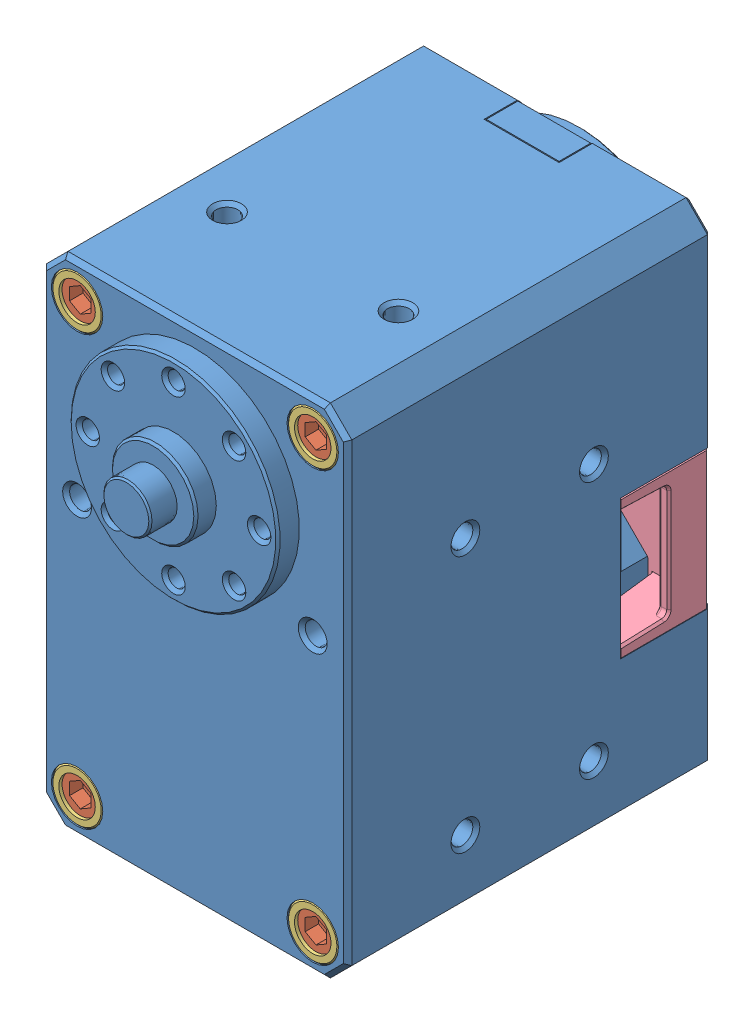
SolidWorks assembly XM430, configuration Default. Lengths in mm.
Overall size (28.5 46.5 42.4).
18 component instances, 4 part files, 0 mates.
Components (placement in the parent):
- DUMMY_DC12-1: DUMMY_DC12 [Default] at origin size (28.5 46.5 42.4)
- WBH_M2_5X12-1: WBH_M2_5X12 [Default] at (-11 8 14.2) size (4.5 4.5 14.5)
- WBH_M2_5X12-2: WBH_M2_5X12 [Default] at (11 8 14.2) size (4.5 4.5 14.5)
- WBH_M2_5X12-3: WBH_M2_5X12 [Default] at (-11 -32 14.2) size (4.5 4.5 14.5)
- WBH_M2_5X12-4: WBH_M2_5X12 [Default] at (11 -32 14.2) size (4.5 4.5 14.5)
- WBH_M2_5X12-5: WBH_M2_5X12 [Default] at (11 -32 -14.2) x (-1 0 0) z (0 0 -1) size (4.5 4.5 14.5)
- WBH_M2_5X12-6: WBH_M2_5X12 [Default] at (-11 -32 -14.2) x (-1 0 0) z (0 0 -1) size (4.5 4.5 14.5)
- WBH_M2_5X12-7: WBH_M2_5X12 [Default] at (11 8 -14.2) x (-1 0 0) z (0 0 -1) size (4.5 4.5 14.5)
- WBH_M2_5X12-8: WBH_M2_5X12 [Default] at (-11 8 -14.2) x (-1 0 0) z (0 0 -1) size (4.5 4.5 14.5)
- DC12_A01_SPACER_RING_1-1: DC12_A01_SPACER_RING_1 [Default] at (11 8 -14.2) x (1 0 0) z (0 1 0) size (4.8 2.8 4.8)
- DC12_A01_SPACER_RING_1-2: DC12_A01_SPACER_RING_1 [Default] at (-11 8 -14.2) x (1 0 0) z (0 1 0) size (4.8 2.8 4.8)
- DC12_A01_SPACER_RING_1-3: DC12_A01_SPACER_RING_1 [Default] at (11 -32 -14.2) x (1 0 0) z (0 1 0) size (4.8 2.8 4.8)
- DC12_A01_SPACER_RING_1-4: DC12_A01_SPACER_RING_1 [Default] at (-11 -32 -14.2) x (1 0 0) z (0 1 0) size (4.8 2.8 4.8)
- DC12_A01_SPACER_RING_1-5: DC12_A01_SPACER_RING_1 [Default] at (-11 -32 14.2) x (-1 0 0) z (0 1 0) size (4.8 2.8 4.8)
- DC12_A01_SPACER_RING_1-6: DC12_A01_SPACER_RING_1 [Default] at (11 -32 14.2) x (-1 0 0) z (0 1 0) size (4.8 2.8 4.8)
- DC12_A01_SPACER_RING_1-7: DC12_A01_SPACER_RING_1 [Default] at (-11 8 14.2) x (-1 0 0) z (0 1 0) size (4.8 2.8 4.8)
- DC12_A01_SPACER_RING_1-8: DC12_A01_SPACER_RING_1 [Default] at (11 8 14.2) x (-1 0 0) z (0 1 0) size (4.8 2.8 4.8)
- DC12_A01_CVR_CABLE_5-1: DC12_A01_CVR_CABLE_5 [Default] at (0 -0.05 0) size (28.5 13.4 8.8)
